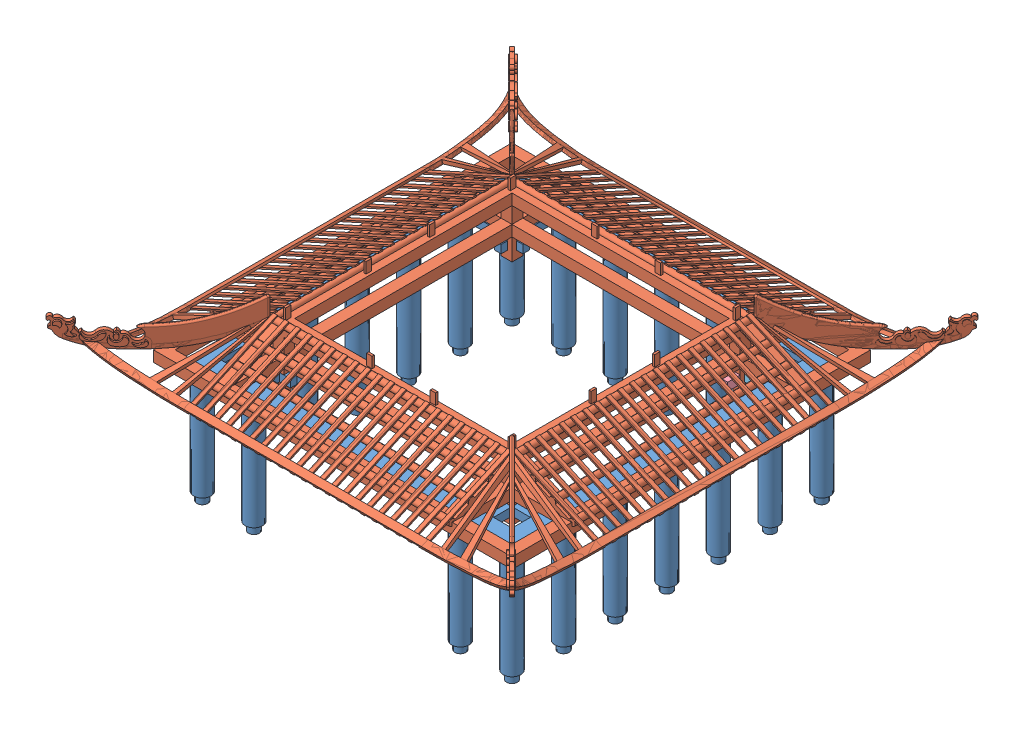
SolidWorks assembly 一层榫卯装配, configuration 默认. Lengths in mm.
Overall size (10017.92 9250 10017.92).
10 component instances, 5 part files, 27 mates.
Components (placement in the parent):
- 梁柱-1: 梁柱 [默认] at (-3889.8161 -818.7427 9320) size (6020 2250 6020)
- 屋顶木架-1: 屋顶木架 [默认] at (-2789.8161 1731.2573 8220) size (10017.92 7450 10017.92)
- 一层插销-2: 一层插销 [默认] at (1525.1839 981.2573 4125) size (25 50 50)
- 一层榫卯短-2: 一层榫卯短 [默认] at (1610.1839 1131.2573 4050) x (0 0 1) z (1 0 0) size (260 150 120)
- 一层榫卯长-2: 一层榫卯长 [默认] at (1610.1839 1131.2573 3240) x (0 0 1) z (1 0 0) size (1050 150 120)
- 一层插销-3: 一层插销 [默认] at (1562.6839 981.2573 4096.6506) x (0.866025 0 0.5) z (-0.5 0 0.866025) size (25 50 50)
- 一层插销-4: 一层插销 [默认] at (1351.8345 1081.2573 3917.5) x (0.5 0 -0.866025) z (0.866025 0 0.5) size (25 50 50)
- 一层榫卯短-3: 一层榫卯短 [默认] at (1380.1839 981.2573 3820) x (-1 0 0) z (0 0 -1) size (260 150 120)
- 一层榫卯长-3: 一层榫卯长 [默认] at (2190.1839 981.2573 3820) x (-1 0 0) z (0 0 -1) size (1050 150 120)
- 一层插销-5: 一层插销 [默认] at (1330.1839 1081.2573 3855) x (0 0 1) z (-1 0 0) size (25 50 50)
Mates (geometry in assembly coordinates):
- 重合1: coincident: plane of 梁柱-1 through (2710.1839 981.2573 8100) normal (0 0 -1); plane of 屋顶木架-1 through (-4751.1438 1131.2573 8100) normal (0 0 1)
- 重合2: coincident: plane of 梁柱-1 through (1490.1839 981.2573 9320) normal (-1 0 0); plane of 屋顶木架-1 through (1490.1839 1131.2573 1858.6713) normal (1 0 0)
- 重合3: coincident: plane of 梁柱-1 through (2710.1839 1131.2573 9320) normal (0 1 0); plane of 屋顶木架-1 through (1610.1839 1131.2573 1858.6713) normal (0 -1 0)
- 重合5: coincident: plane of 梁柱-1 through (1580.1839 1011.2573 3010) normal (-1 0 0); plane of 一层榫卯长-2 through (1580.1839 1131.2573 3100) normal (1 0 0)
- 重合6: coincident: plane of 梁柱-1 through (2260.1839 -818.7427 3100) normal (0 0 -1); plane of 一层榫卯长-2 through (1610.1839 1131.2573 3100) normal (0 0 -1)
- 重合7: coincident: plane of 梁柱-1 through (1580.1839 1101.2573 3010) normal (0 -1 0); plane of 一层榫卯长-2 through (1610.1839 1101.2573 3100) normal (0 1 0)
- 重合9: coincident: plane of 一层榫卯长-2 through (1525.1839 981.2573 4150) normal (-1 0 0); plane of 一层榫卯短-2 through (1525.1839 1031.2573 4050) normal (1 0 0)
- 重合10: coincident: line of 一层榫卯短-2 through (1525.1839 981.2573 4150) axis (1 0 0); plane of 一层榫卯长-2 through (1610.1839 1131.2573 4150) normal (0 0 1)
- 重合11: coincident: plane of 一层榫卯短-2 through (1610.1839 981.2573 4250) normal (0 -1 0); plane of 一层榫卯长-2 through (1610.1839 981.2573 3850) normal (0 -1 0)
- 重合12: coincident: plane of 一层插销-2 through (1525.1839 1031.2573 4125) normal (-0.965926 0 0.258819); plane of 一层榫卯短-2 through (1512.1278 1031.2573 4076.274) normal (0.965926 0 -0.258819)
- 重合13: coincident: plane of 一层插销-2 through (1525.1839 1031.2573 4125) normal (0.258819 0 0.965926); plane of 一层榫卯长-2 through (1825.7399 1131.2573 4044.4662) normal (-0.258819 0 -0.965926)
- 重合14: coincident: plane of 一层插销-2 through (1525.1839 981.2573 4125) normal (0 -1 0); plane of 一层榫卯短-2 through (1610.1839 981.2573 4250) normal (0 -1 0)
- 重合15: coincident: plane of 一层榫卯短-2 through (1590.0284 1031.2573 4044.5994) normal (-0.965926 0 -0.258819); plane of 一层插销-3 through (1575.1839 1031.2573 4100) normal (0.965926 0 0.258819)
- 重合16: coincident: plane of 一层榫卯短-2 through (1607.8393 1031.2573 4058.75) normal (-0.258819 0 0.965926); plane of 一层插销-3 through (1575.1839 1031.2573 4050) normal (0.258819 0 -0.965926)
- 重合17: coincident: plane of 一层榫卯短-2 through (1610.1839 981.2573 4250) normal (0 -1 0); plane of 一层插销-3 through (1562.6839 981.2573 4096.6506) normal (0 -1 0)
- 重合18: coincident: plane of 一层榫卯长-3 through (2330.1839 981.2573 3910) normal (0 0 1); plane of 梁柱-1 through (2420.1839 1011.2573 3910) normal (0 0 -1)
- 重合19: coincident: plane of 梁柱-1 through (2420.1839 1011.2573 3850) normal (0 1 0); plane of 一层榫卯长-3 through (2330.1839 1011.2573 3820) normal (0 -1 0)
- 重合20: coincident: plane of 梁柱-1 through (2330.1839 -818.7427 3170) normal (1 0 0); plane of 一层榫卯长-3 through (2330.1839 981.2573 3820) normal (1 0 0)
- 重合22: coincident: plane of 一层榫卯短-3 through (1380.1839 1081.2573 3855) normal (0 0 1); plane of 一层榫卯长-3 through (1280.1839 1131.2573 3855) normal (0 0 -1)
- 重合23: coincident: plane of 一层榫卯短-3 through (1280.1839 1081.2573 3820) normal (1 0 0); plane of 一层榫卯长-3 through (1280.1839 981.2573 3820) normal (-1 0 0)
- 重合24: coincident: plane of 一层榫卯短-3 through (1180.1839 1131.2573 3820) normal (0 1 0); plane of 一层榫卯长-3 through (1580.1839 1131.2573 3820) normal (0 1 0)
- 重合25: coincident: plane of 一层插销-4 through (1351.8345 1131.2573 3917.5) normal (-0.258819 0 0.965926); plane of 一层榫卯短-3 through (1353.9098 1081.2573 3918.0561) normal (0.258819 0 -0.965926)
- 重合26: coincident: plane of 一层插销-4 through (1351.8345 1131.2573 3917.5) normal (0.965926 0 0.258819); plane of 一层榫卯短-3 through (1378.1085 1081.2573 3819.4439) normal (-0.965926 0 -0.258819)
- 重合27: coincident: plane of 一层插销-4 through (1351.8345 1131.2573 3917.5) normal (0 1 0); plane of 一层榫卯短-3 through (1180.1839 1131.2573 3820) normal (0 1 0)
- 重合28: coincident: plane of 一层榫卯短-3 through (1385.5845 1081.2573 3840.1554) normal (0.258819 0 0.965926); plane of 一层插销-5 through (1330.1839 1131.2573 3855) normal (-0.258819 0 -0.965926)
- 重合29: coincident: plane of 一层榫卯长-3 through (1379.0429 981.2573 4037.3446) normal (0.965926 0 -0.258819); plane of 一层插销-5 through (1330.1839 1131.2573 3855) normal (-0.965926 0 0.258819)
- 重合30: coincident: plane of 一层榫卯短-3 through (1180.1839 1131.2573 3820) normal (0 1 0); plane of 一层插销-5 through (1330.1839 1131.2573 3855) normal (0 1 0)
